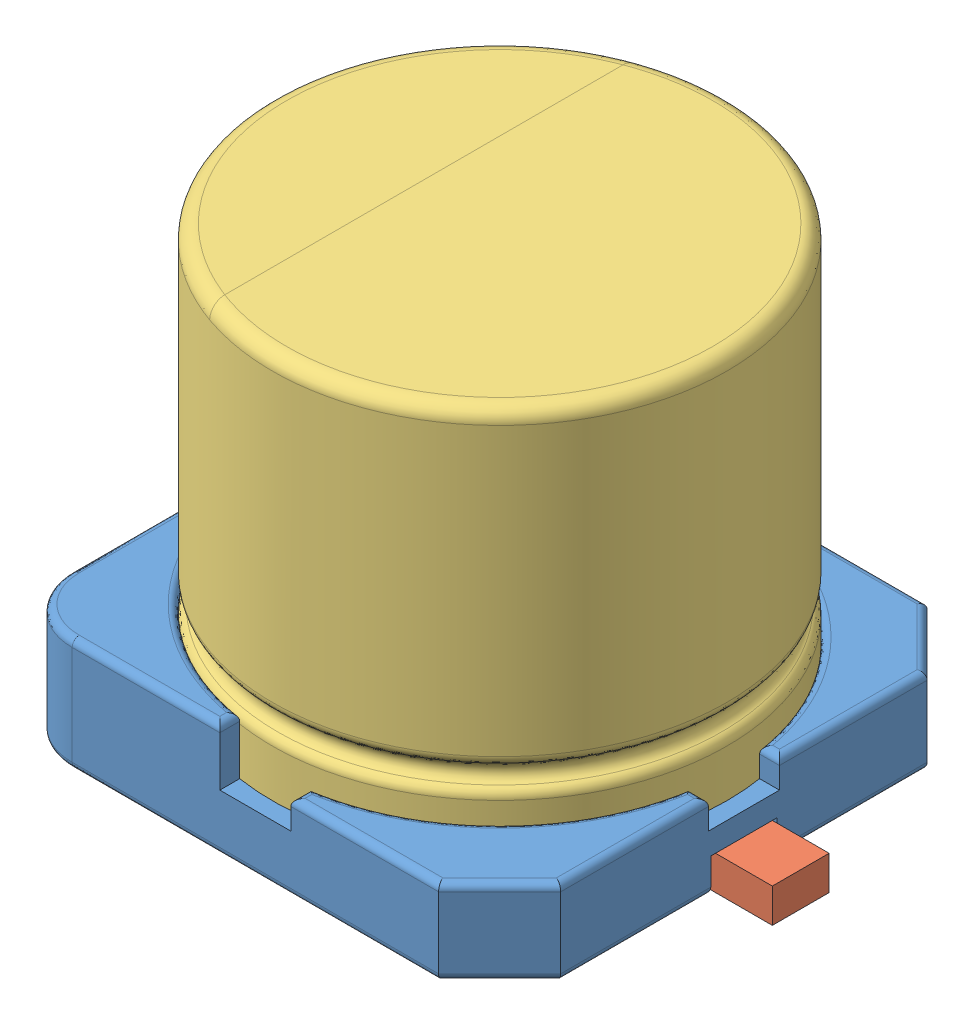
SolidWorks assembly SMD Aluminum Electrolytic Capacitor (Generic), configuration Nichicon (UZG)(A) SQ(4.3) D(4) (L3.9). Lengths in mm.
Overall size (5.3 3.9 4.3).
4 component instances, 3 part files, 9 mates.
Components (placement in the parent):
- SMD AEC (Base)-1: SMD AEC (Base) [Predeterminado] at origin size (4.3 1 4.3)
- SMD AEC (Pin)-1: SMD AEC (Pin) [Predeterminado] at (0.75 0 0) size (2.05 1.25 0.5)
- SMD AEC (Cylinder)-1: SMD AEC (Cylinder) [Predeterminado] at origin size (4 3.4 4)
- SMD AEC (Pin)-3: SMD AEC (Pin) [Predeterminado] at (-0.75 0 0) x (-1 0 0) z (0 0 -1) size (2.05 1.25 0.5)
Mates (geometry in assembly coordinates):
- Coincidente1: coincident aligned: plane of SMD AEC (Base)-1 through (0 0 0) normal (0 0 1)
- Coincidente2: coincident aligned: plane of SMD AEC (Base)-1 through (0 0 0) normal (0 1 0)
- Coincidente3: coincident aligned: plane of SMD AEC (Base)-1 through (0 0 0) normal (1 0 0)
- Coincidente4: coincident aligned: plane of SMD AEC (Pin)-1 through (0.75 0 0) normal (0 0 1)
- Coincidente5: coincident aligned: plane of SMD AEC (Pin)-1 through (0.75 0 0) normal (0 1 0)
- Coincidente6: coincident: plane of SMD AEC (Pin)-1 through (0.75 0 0) normal (1 0 0)
- Coincidente7: coincident aligned: plane of SMD AEC (Cylinder)-1 through (0 0 0) normal (0 0 1)
- Coincidente8: coincident aligned: plane of SMD AEC (Cylinder)-1 through (0 0 0) normal (0 1 0)
- Coincidente9: coincident aligned: plane of SMD AEC (Cylinder)-1 through (0 0 0) normal (1 0 0)
